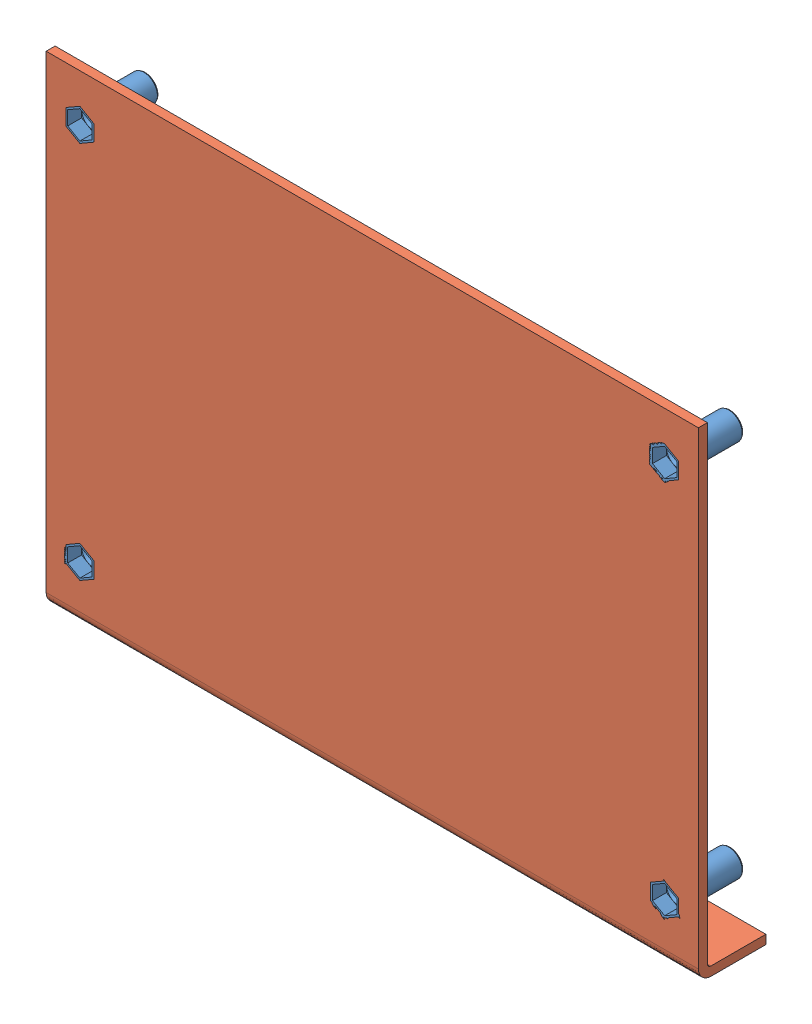
SolidWorks assembly VentClose, configuration Default. Lengths in mm.
Overall size (145 107 15).
8 component instances, 3 part files, 9 mates.
Components (placement in the parent):
- ecrou_01i040ahb030x_3-1: ecrou_01i040ahb030x_3 [Default] at (-3.9311 41.5479 -11.5) x (1 0 0) z (0 -1 0) size (9.24 14.5 9.24)
- ecrou_01i040ahb030x_3-2: ecrou_01i040ahb030x_3 [Default] at (-3.9311 -42.5931 -11.5) x (1 0 0) z (0 -1 0) size (9.24 14.5 9.24)
- ecrou_01i040ahb030x_3-3: ecrou_01i040ahb030x_3 [Default] at (-133.9311 -42.5931 -11.5) x (1 0 0) z (0 -1 0) size (9.24 14.5 9.24)
- ecrou_01i040ahb030x_3-4: ecrou_01i040ahb030x_3 [Default] at (-133.9311 41.5479 -11.5) x (1 0 0) z (0 -1 0) size (9.24 14.5 9.24)
- Vents_F_1-1: Vents_F_1 [Default] at (-148.9311 -243.4516 4) x (-1 0 0) z (0 0 -1) size (145 107 15)
- CLS-M4-0-PennEngineering-01-13-2017_F-9: CLS-M4-0-PennEngineering-01-13-2017_F [Default] at (-9.7311 -53.7924 -5.9) x (0 1 0) z (0 0 1) size (2.77 7.87 7.87)
- CLS-M4-0-PennEngineering-01-13-2017_F-3: CLS-M4-0-PennEngineering-01-13-2017_F [Default] at (-52.3311 -53.7924 -5.9) x (0 1 0) z (0 0 1) size (2.77 7.87 7.87)
- CLS-M4-0-PennEngineering-01-13-2017_F-5: CLS-M4-0-PennEngineering-01-13-2017_F [Default] at (-94.9311 -53.7924 -5.9) x (0 1 0) z (0 0 1) size (2.77 7.87 7.87)
Mates (geometry in assembly coordinates):
- Coincident1: coincident aligned: plane of ecrou_01i040ahb030x_3-1 through (-1.9659 41.5479 3) normal (0 0 1); plane of Vents_F_1-1 through (-148.9311 -243.4516 3) normal (0 0 1)
- Width1: width anti-aligned: plane of ecrou_01i040ahb030x_3-2 through (-0.9311 -42.5931 2.7691) normal (1 0 0); plane of ecrou_01i040ahb030x_3-2 through (-6.9311 -42.5931 2.7691) normal (-1 0 0); plane of Vents_F_1-1 through (-0.8311 -44.3828 0.9989) normal (-1 0 0); plane of Vents_F_1-1 through (-7.0311 -40.8033 0.9989) normal (1 0 0)
- Width2: width anti-aligned: plane of ecrou_01i040ahb030x_3-2 through (-5.4311 -45.1911 2.7691) normal (-0.5 -0.866025 0); plane of ecrou_01i040ahb030x_3-2 through (-2.4311 -39.995 2.7691) normal (0.5 0.866025 0); plane of Vents_F_1-1 through (-7.0311 -44.3828 0.9989) normal (0.5 0.866025 0); plane of Vents_F_1-1 through (-0.8311 -40.8033 0.9989) normal (-0.5 -0.866025 0)
- Coincident2: coincident anti-aligned: plane of Vents_F_1-1 through (-141.4311 -53.0224 -12) normal (0 1 0); plane of CLS-M4-0-PennEngineering-01-13-2017_F-9 through (-9.7311 -53.0224 -3.9325) normal (0 -1 0)
- Concentric1: concentric anti-aligned: cylinder of Vents_F_1-1 through (-9.7311 51.9776 -5.9) axis (0 -1 0) radius 2.5; cylinder of CLS-M4-0-PennEngineering-01-13-2017_F-9 through (-9.7311 -52.1404 -5.9) axis (0 1 0) radius 3.935
- Coincident3: coincident aligned: plane of CLS-M4-0-PennEngineering-01-13-2017_F-9 through (-9.7311 -51.0224 -4.0506) normal (0 1 0); plane of CLS-M4-0-PennEngineering-01-13-2017_F-3 through (-52.3311 -51.0224 -4.0506) normal (0 1 0)
- Coincident4: coincident aligned: plane of CLS-M4-0-PennEngineering-01-13-2017_F-3 through (-52.3311 -51.0224 -4.0506) normal (0 1 0); plane of CLS-M4-0-PennEngineering-01-13-2017_F-5 through (-94.9311 -51.0224 -4.0506) normal (0 1 0)
- Concentric2: concentric anti-aligned: cylinder of Vents_F_1-1 through (-52.3311 51.9776 -5.9) axis (0 -1 0) radius 2.5; cylinder of CLS-M4-0-PennEngineering-01-13-2017_F-3 through (-52.3311 -52.1404 -5.9) axis (0 1 0) radius 3.935
- Concentric3: concentric anti-aligned: cylinder of Vents_F_1-1 through (-94.9311 51.9776 -5.9) axis (0 -1 0) radius 2.5; cylinder of CLS-M4-0-PennEngineering-01-13-2017_F-5 through (-94.9311 -52.1404 -5.9) axis (0 1 0) radius 3.935
